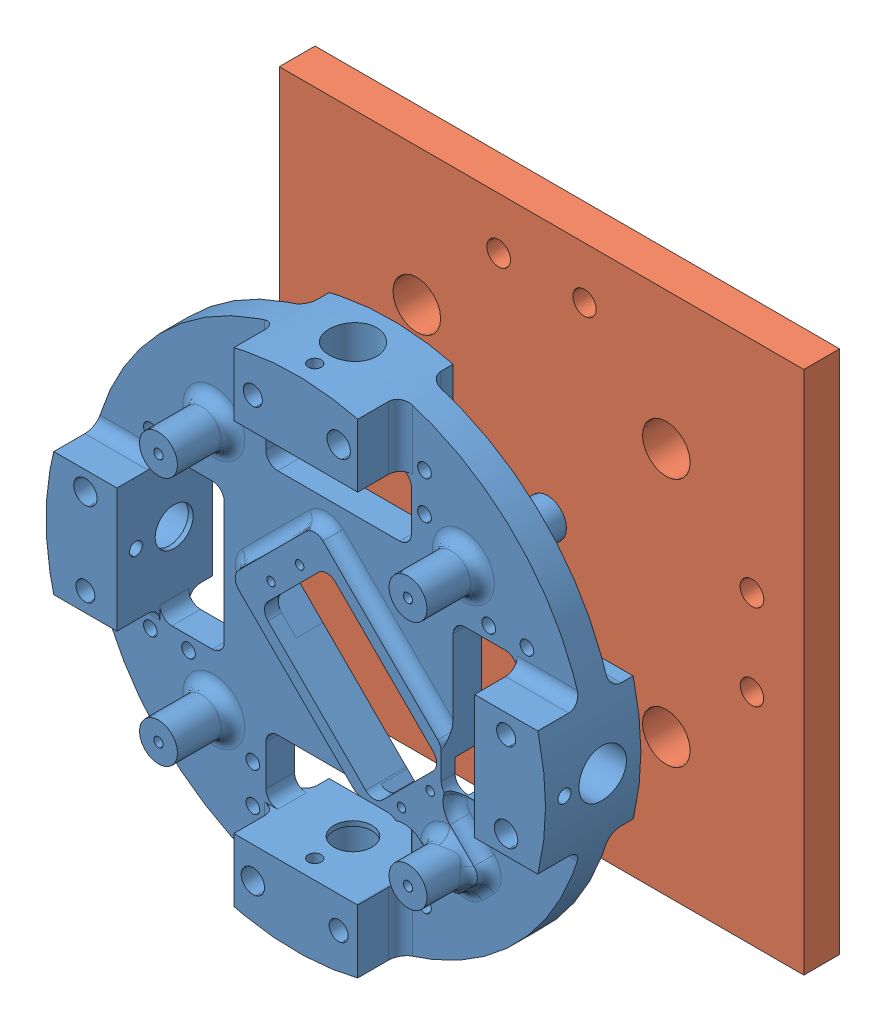
SolidWorks assembly Base_Plate_Jig_Asm, configuration Default. Lengths in mm.
Overall size (139.7 139.7 87.93).
2 component instances, 2 part files, 2 mates.
Components (placement in the parent):
- BasePlate-1: BasePlate [Default] at (-86.1356 17.3192 1.5076) size (133.05 133.05 87.93)
- Base_Plate_Jig-1: Base_Plate_Jig [Default] at (-86.1356 17.3192 -58.2476) size (139.7 139.7 60.32)
Mates (geometry in assembly coordinates):
- Coincident7: coincident aligned: axis of BasePlate-1 through (-86.1356 17.3192 -8.6524) axis (0 0 1); line of Base_Plate_Jig-1 through (-86.1356 17.3192 -59.2001) axis (0 0 1)
- Parallel1: parallel anti-aligned: line of BasePlate-1 through (-116.6156 1.0986 5.3176) axis (0 1 0); line of Base_Plate_Jig-1 through (-155.9856 87.1692 -48.7226) axis (0 -1 0)
